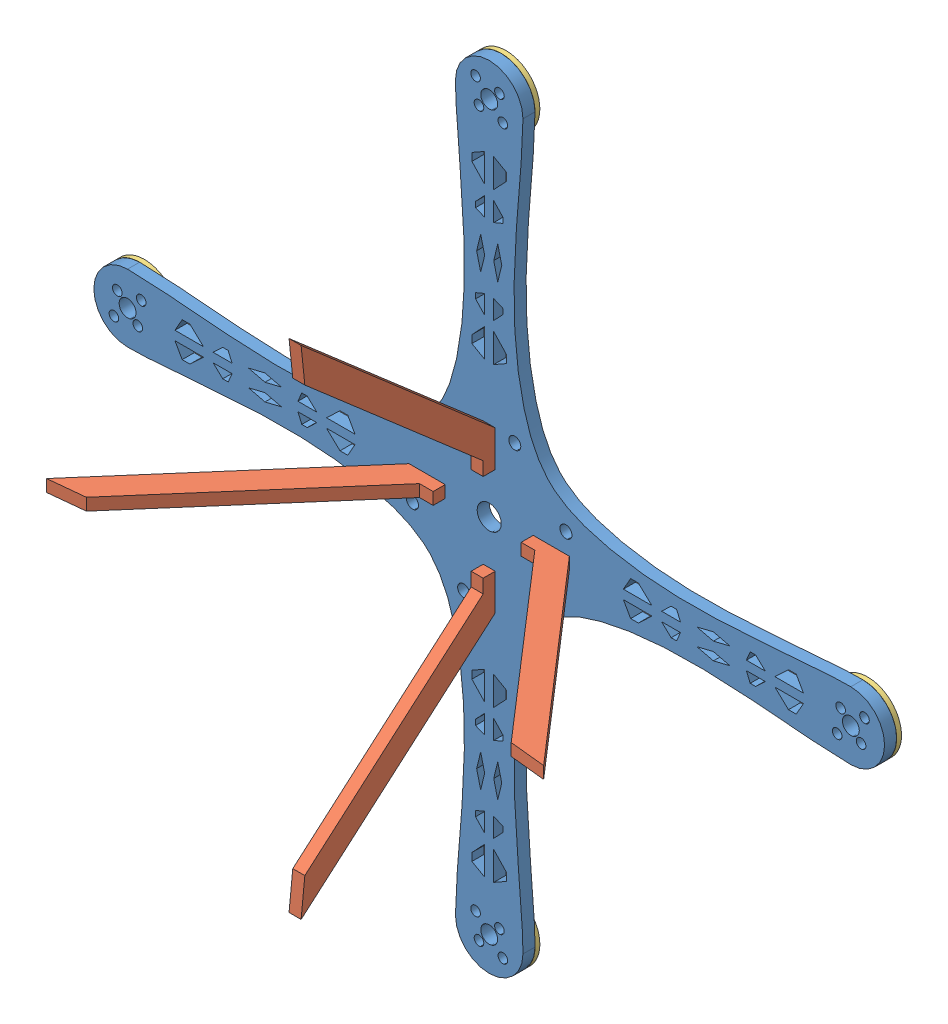
SolidWorks assembly Sabbir_drone, configuration Default. Lengths in mm.
Overall size (328 328 87.52).
9 component instances, 3 part files, 6 mates.
Components (placement in the parent):
- Sabbir_drone-1: Sabbir_drone [Default] at (98.5745 162.5415 270.2192) size (328 328 5)
- Sabbir_drone_leg-1: Sabbir_drone_leg [Default] at (101.0745 167.503 425.2192) x (0 0 1) z (-1 0 0) size (85.52 84.84 5)
- Sabbir_drone_leg-2: Sabbir_drone_leg [Default] at (93.613 165.0415 425.2192) x (0 0 1) z (0 -1 0) size (85.52 84.84 5)
- Sabbir_drone_leg-3: Sabbir_drone_leg [Default] at (96.0745 157.58 425.2192) x (0 0 1) z (1 0 0) size (85.52 84.84 5)
- Sabbir_drone_leg-4: Sabbir_drone_leg [Default] at (103.536 160.0415 425.2192) x (0 0 1) z (0 1 0) size (85.52 84.84 5)
- Sabbir_drone_motor_holder-1: Sabbir_drone_motor_holder [Default] at (98.5745 162.5415 268.2192) size (28 28 2)
- Sabbir_drone_motor_holder-2: Sabbir_drone_motor_holder [Default] at (98.5745 162.5415 268.2192) x (0 1 0) z (0 0 1) size (28 28 2)
- Sabbir_drone_motor_holder-3: Sabbir_drone_motor_holder [Default] at (98.5745 162.5415 268.2192) x (-1 0 0) z (0 0 1) size (28 28 2)
- Sabbir_drone_motor_holder-4: Sabbir_drone_motor_holder [Default] at (98.5745 162.5415 268.2192) x (0 -1 0) z (0 0 1) size (28 28 2)
Mates (geometry in assembly coordinates):
- Coincident7: coincident: plane of Sabbir_drone-1 through (101.0745 162.5415 275.2192) normal (-1 0 0); plane of Sabbir_drone_leg-1 through (101.0745 167.503 425.2192) normal (1 0 0)
- Coincident8: coincident: plane of Sabbir_drone-1 through (98.5745 180.7915 275.2192) normal (0 1 0); plane of Sabbir_drone_leg-1 through (96.0745 180.7915 270.2192) normal (0 -1 0)
- Coincident9: coincident: plane of Sabbir_drone-1 through (98.5745 162.5415 270.2192) normal (0 0 -1); plane of Sabbir_drone_leg-1 through (96.0745 185.7915 270.2192) normal (0 0 -1)
- Coincident10: coincident: plane of Sabbir_drone-1 through (98.5745 162.5415 270.2192) normal (0 0 -1); plane of Sabbir_drone_motor_holder-1 through (98.5745 162.5415 270.2192) normal (0 0 1)
- Concentric1: concentric: cylinder of Sabbir_drone-1 through (-51.4255 162.5415 275.2192) axis (0 0 -1) radius 3.5; circle of Sabbir_drone_motor_holder-1
- Concentric2: concentric: cylinder of Sabbir_drone-1 through (-47.1829 158.2988 275.2192) axis (0 0 -1) radius 2; cylinder of Sabbir_drone_motor_holder-1 through (-47.1829 158.2988 270.2192) axis (0 0 -1) radius 1.25
